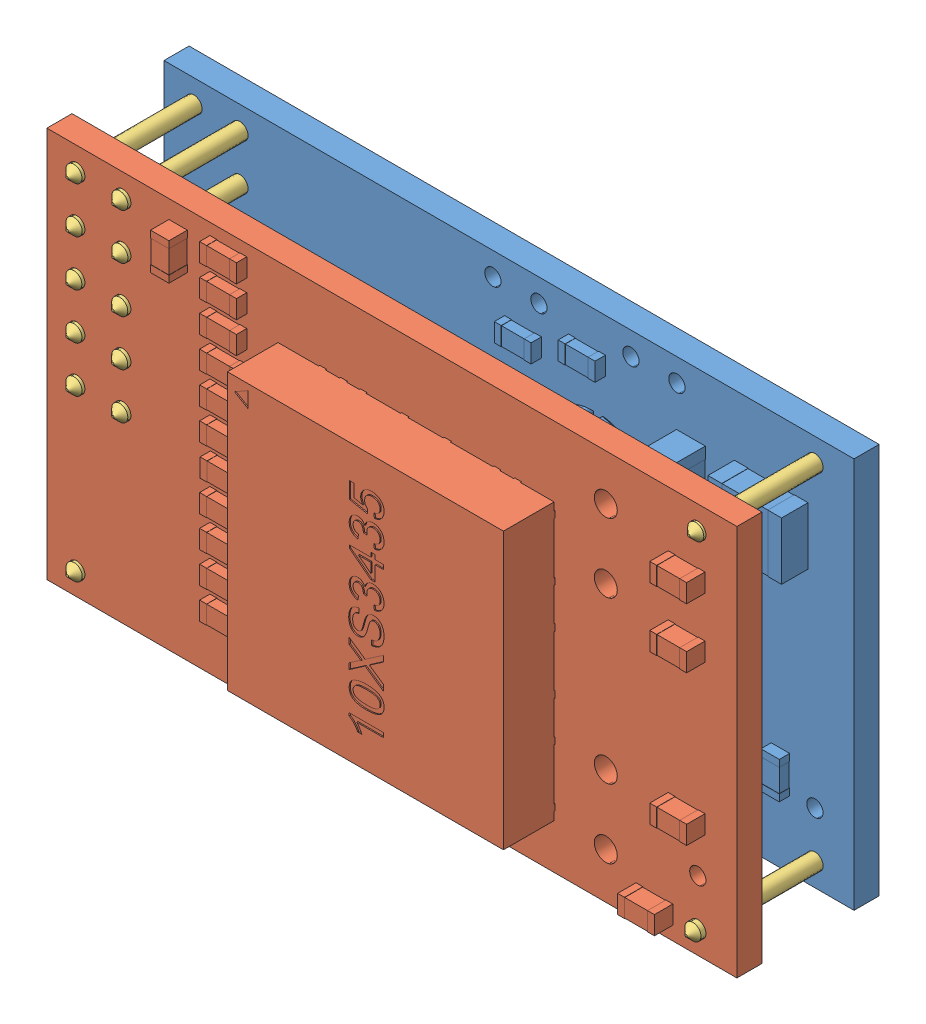
SolidWorks assembly Сборка, configuration По умолчанию. Lengths in mm.
Overall size (30 17 11.43).
15 component instances, 3 part files, 16 mates.
Components (placement in the parent):
- CPU_PCB-1: CPU_PCB [По умолчанию] at (0.1503 24.8596 21.126) size (30 17 7.43)
- SWITCH_PCB-1: SWITCH_PCB [По умолчанию] at (0.1503 24.8596 26.2175) size (30 17 4.59)
- Wire-1: Wire [По умолчанию] at (27.1503 9.8596 19.7296) x (1 0 0) z (0 -1 0) size (0.7 7 0.7)
- Wire-2: Wire [По умолчанию] at (2.1503 24.8595 19.6442) x (0.999351 -0.03603 0) z (-0.03603 -0.999351 0) size (0.7 7 0.7)
- Wire-3: Wire [По умолчанию] at (0.1503 22.8595 26.6341) x (0.975087 -0.221823 0) z (0.221823 0.975087 0) size (0.7 7 0.7)
- Wire-4: Wire [По умолчанию] at (0.1503 24.8595 19.6398) x (0.990252 -0.139291 0) z (-0.139291 -0.990252 0) size (0.7 7 0.7)
- Wire-5: Wire [По умолчанию] at (0.1503 20.8595 19.6451) x (0.963546 0.267542 0) z (0.267542 -0.963546 0) size (0.7 7 0.7)
- Wire-6: Wire [По умолчанию] at (2.1503 22.8595 26.6438) x (0.364696 -0.931127 0) z (0.931127 0.364696 0) size (0.7 7 0.7)
- Wire-7: Wire [По умолчанию] at (0.1503 16.8596 26.6403) x (0.999646 0.026589 0) z (-0.026589 0.999646 0) size (0.7 7 0.7)
- Wire-8: Wire [По умолчанию] at (2.1503 16.8596 26.648) x (0.969049 0.246868 0) z (-0.246868 0.969049 0) size (0.7 7 0.7)
- Wire-9: Wire [По умолчанию] at (0.1503 18.8596 26.643) x (0.804618 -0.593793 0) z (0.593793 0.804618 0) size (0.7 7 0.7)
- Wire-10: Wire [По умолчанию] at (2.1503 18.8596 19.6515) x (0.940183 0.34067 0) z (0.34067 -0.940183 0) size (0.7 7 0.7)
- Wire-11: Wire [По умолчанию] at (2.1503 20.8595 19.6505) x (0.967842 -0.251559 0) z (-0.251559 -0.967842 0) size (0.7 7 0.7)
- Wire-12: Wire [По умолчанию] at (0.1503 9.8596 26.6306) x (0.994265 0.106948 0) z (-0.106948 0.994265 0) size (0.7 7 0.7)
- Wire-13: Wire [По умолчанию] at (27.1503 24.8595 26.6061) x (0.998082 -0.061899 0) z (0.061899 0.998082 0) size (0.7 7 0.7)
Mates (geometry in assembly coordinates):
- Совпадение1: coincident aligned: plane of CPU_PCB-1 through (-1.1497 25.8596 20.0346) normal (-1 0 0); plane of SWITCH_PCB-1 through (-1.1497 25.8596 25.126) normal (-1 0 0)
- Совпадение2: coincident aligned: plane of CPU_PCB-1 through (28.8503 25.8596 20.0346) normal (0 1 0); plane of SWITCH_PCB-1 through (28.8503 25.8596 25.126) normal (0 1 0)
- Расстояние1: distance = 4 mm anti-aligned: plane of CPU_PCB-1 through (-1.1497 8.8596 21.126) normal (0 0 1); plane of SWITCH_PCB-1 through (-1.1497 8.8596 25.126) normal (0 0 -1)
- Совпадение4: coincident: circle of CPU_PCB-1; cone of Wire-1 through (27.1503 9.8596 20.0296) axis (0 0 -1)
- Концентричный1: concentric aligned: circle of CPU_PCB-1; circle of Wire-4
- Концентричный2: concentric aligned: circle of CPU_PCB-1; circle of Wire-2
- Концентричный3: concentric anti-aligned: circle of CPU_PCB-1; circle of Wire-3
- Концентричный4: concentric anti-aligned: circle of CPU_PCB-1; circle of Wire-6
- Концентричный5: concentric aligned: circle of CPU_PCB-1; circle of Wire-5
- Концентричный6: concentric anti-aligned: circle of CPU_PCB-1; circle of Wire-11
- Концентричный7: concentric anti-aligned: circle of CPU_PCB-1; circle of Wire-10
- Концентричный8: concentric aligned: circle of CPU_PCB-1; circle of Wire-9
- Концентричный9: concentric aligned: circle of CPU_PCB-1; circle of Wire-8
- Концентричный10: concentric aligned: circle of Wire-7; circle of CPU_PCB-1
- Концентричный11: concentric anti-aligned: circle of CPU_PCB-1; circle of Wire-13
- Концентричный12: concentric anti-aligned: circle of SWITCH_PCB-1; circle of Wire-12
